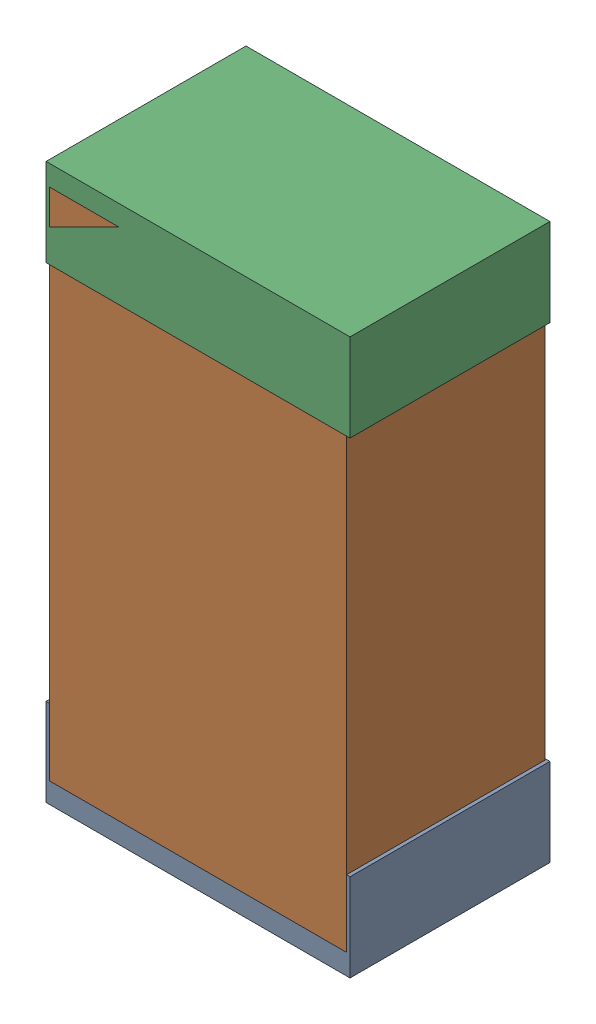
SolidWorks assembly R31Kanaloa_v2.0.0_Motor, configuration Default. Lengths in mm.
Overall size (1.3 2.38 0.85).
6 component instances, 2 part files, 0 mates.
Components (placement in the parent):
- 330415056-1: 330415056 [Default] at (127 93.234 -1.9574) size (1.3 0.38 0.85)
  - Extruded_2-1: Extruded_2 [Default] at origin size (1.3 0.38 0.85)
- 334787376-1: 334787376 [Default] at (127 94.234 -1.9524) size (1.27 2.2 0.85)
  - Extruded_16-1: Extruded_16 [Default] at origin size (1.27 2.2 0.85)
- 330415056-2: 330415056 [Default] at (127 95.234 -1.9574) size (1.3 0.38 0.85)
  - Extruded_2-1: Extruded_2 [Default] at origin size (1.3 0.38 0.85)
